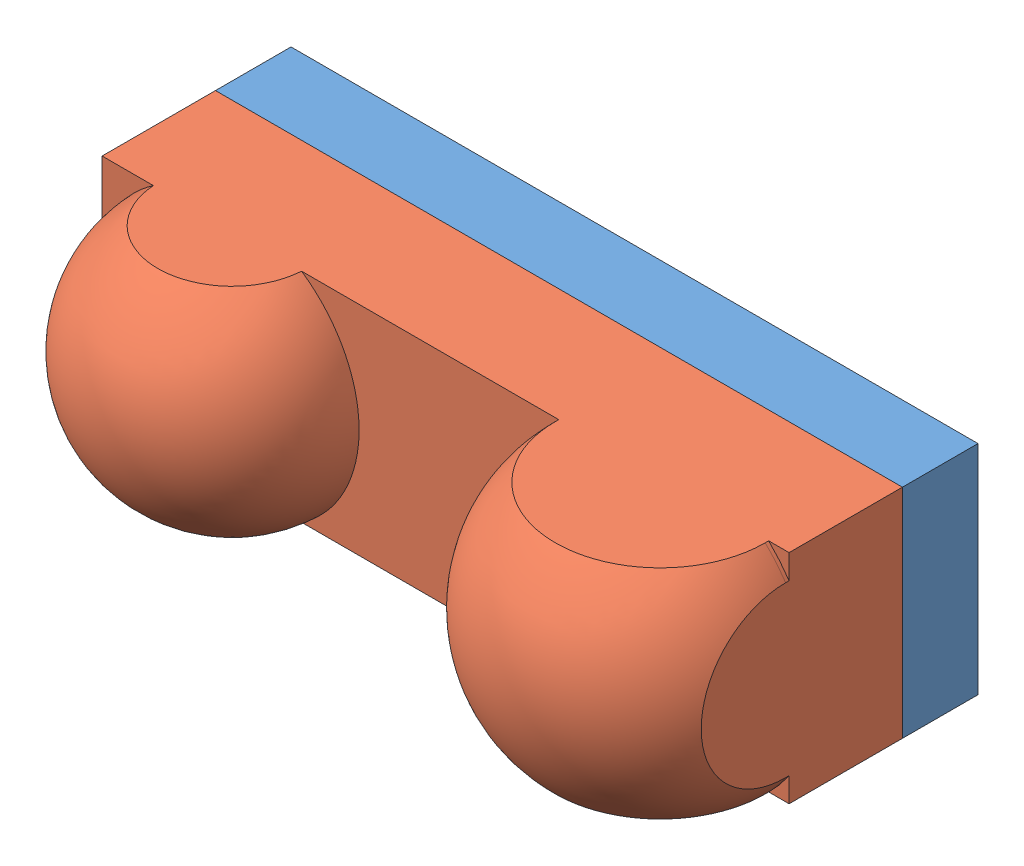
SolidWorks assembly TFBS4711, configuration По умолчанию. Lengths in mm.
Overall size (6 4.12 4).
9 component instances, 3 part files, 0 mates.
Components (placement in the parent):
- TFBS4711.STEP-1: TFBS4711.STEP [По умолчанию] at origin size (6 4.12 4)
  - PLATINE.STEP-1: PLATINE.STEP [По умолчанию] at (460.1067 351.5107 0.33) size (6 1.9 0.66)
  - GEHAEUSE.STEP-1: GEHAEUSE.STEP [По умолчанию] at (460.1067 351.5107 1.155) size (6 4.12 3.31)
  - KONTAKT.STEP-1: KONTAKT.STEP [По умолчанию] at (457.7367 350.7707 -0.015) size (0.58 0.42 0.72)
  - KONTAKT.STEP-2: KONTAKT.STEP [По умолчанию] at (458.6867 350.7707 -0.015) size (0.58 0.42 0.72)
  - KONTAKT.STEP-3: KONTAKT.STEP [По умолчанию] at (459.6367 350.7707 -0.015) size (0.58 0.42 0.72)
  - KONTAKT.STEP-4: KONTAKT.STEP [По умолчанию] at (460.5867 350.7707 -0.015) size (0.58 0.42 0.72)
  - KONTAKT.STEP-5: KONTAKT.STEP [По умолчанию] at (461.5367 350.7707 -0.015) size (0.58 0.42 0.72)
  - KONTAKT.STEP-6: KONTAKT.STEP [По умолчанию] at (462.4867 350.7707 -0.015) size (0.58 0.42 0.72)
